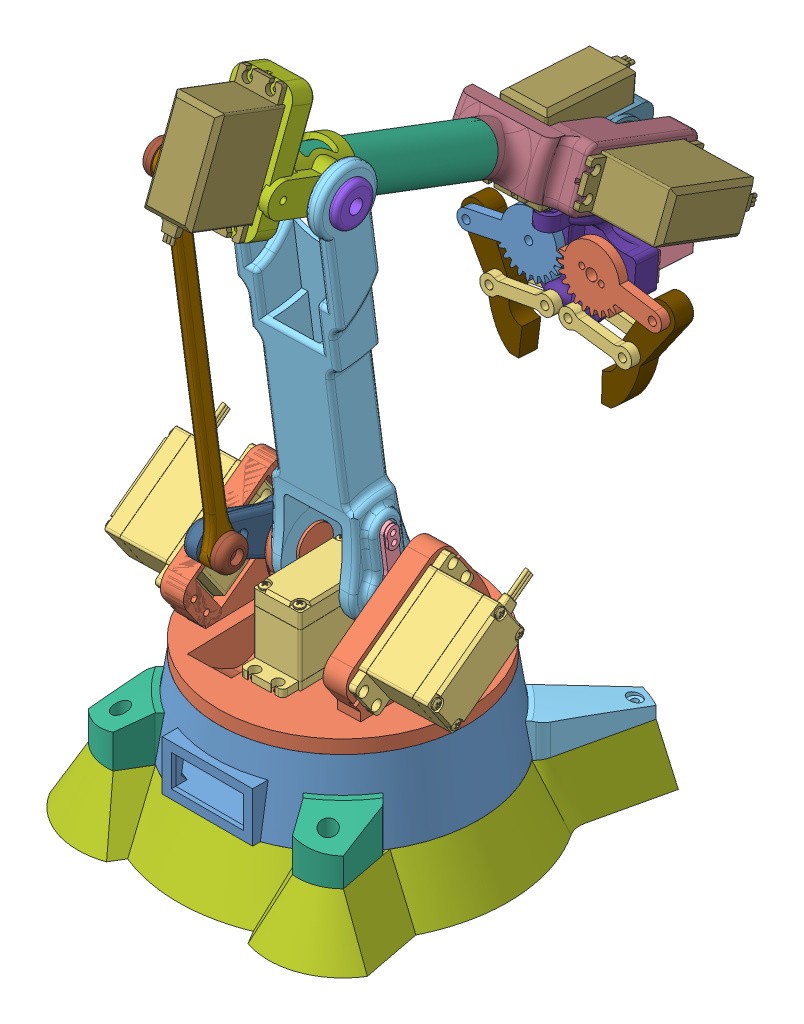
SolidWorks assembly Ensamblaje_BrazoAntropomorfico, configuration Predeterminado. Lengths in mm.
Overall size (151.9 310.82 225.14).
38 component instances, 26 part files, 98 mates.
Components (placement in the parent):
- Base_A-1: Base_A [Predeterminado] at (-3.433 0.4074 120) size (120 34 120)
- Shoulder-1: Shoulder [Predeterminado] at (-7.5517 101.6574 271.2283) x (-0.999641 0 0.026796) z (0 -1 0) size (110 110 66.97)
- DS3225MG-1: DS3225MG [Default] at (-3.433 -8.1926 120) x (0.026796 0 0.999641) z (0 -1 0) size (62.25 20.4 45.91)
- sk7_2-1: sk7_2 [По умолчанию] at (-3.433 -4.5926 120) x (0.707107 0 -0.707107) z (0 -1 0) size (34.33 14.5 6)
- UpperArm-1: UpperArm [Predeterminado] at (-2.865 194.9971 141.1893) x (-0.999641 0 0.026796) z (-0.02656 0.132481 -0.99083) size (45.4 189 30)
- LowerArm_B-1: LowerArm_B [Predeterminado] at (-3.0969 113.8716 19.1086) x (0.999641 0 -0.026796) z (-0.009844 0.930079 -0.367227) size (20 100 20)
- Elbow_A-1: Elbow_A [Predeterminado] at (-2.865 194.9971 141.1893) x (0.999641 0 -0.026796) z (0.009844 -0.930079 0.367227) size (39.5 63 55)
- Elbow_B-1: Elbow_B [Predeterminado] at (4.2269 149.451 93.4114) x (0.999641 0 -0.026796) z (0.016662 0.783182 0.621569) size (9.4 18 18)
- Elbow_B-2: Elbow_B [Predeterminado] at (-9.4831 203.9334 206.6401) x (-0.999641 0 0.026796) z (-0.026796 0 -0.999641) size (9.4 18 18)
- sk7_2-2: sk7_2 [По умолчанию] at (-37.1209 36.4074 120.903) x (0.024922 0.367359 0.929745) z (0.999641 0 -0.026796) size (34.33 14.5 6)
- sk7_2-3: sk7_2 [По умолчанию] at (21.2582 36.4074 119.3381) x (0.00355 0.991186 0.132433) z (-0.999641 0 0.026796) size (34.33 14.5 6)
- DS3225MG-2: DS3225MG [Default] at (17.4595 36.4074 119.44) x (0.02195 -0.573576 0.818858) z (-0.999641 0 0.026796) size (62.25 20.4 45.91)
- DS3225MG-3: DS3225MG [Default] at (-33.3222 36.4074 120.8012) x (0.02195 -0.573576 0.818858) z (0.999641 0 -0.026796) size (62.25 20.4 45.91)
- Elbow_C-1: Elbow_C [Predeterminado] at (-44.9671 11.6675 218.9112) x (-0.999641 0 0.026796) z (-0.02656 0.132481 -0.99083) size (5.67 174 14)
- Elbow_E-1: Elbow_E [Predeterminado] at (-7.0649 232.3614 275.5713) x (-0.999641 0 0.026796) z (-0.024922 -0.367359 -0.929745) size (16 20 57)
- Elbow_D-1: Elbow_D [Predeterminado] at (-46.6763 121.703 173.8077) x (-0.999641 0 0.026796) z (0.006088 -0.973848 0.227119) size (5 14 14)
- Elbow_D-2: Elbow_D [Predeterminado] at (4.4293 190.8188 108.4261) x (0.999641 0 -0.026796) z (0.026363 -0.179135 0.983471) size (5 14 14)
- Servo Motor MG996R_r1-1: Servo Motor MG996R_r1 [Default] at (-1.4531 226.8291 193.8608) x (-0.009844 0.930079 -0.367227) z (-0.999641 0 0.026796) size (55.8 47.4 21)
- LowerArm_A-1: LowerArm_A [Predeterminado] at (-22.8328 142.9423 9.885) x (0.999641 0 -0.026796) z (-0.009844 0.930079 -0.367227) size (52 84.05 26.47)
- Wrist_A-1: Wrist_A [Predeterminado] at (-61.7574 140.4489 24.7051) x (0.026699 0.08517 0.996009) z (0.999641 0 -0.026796) size (55 24 14.25)
- Wrist_B-1: Wrist_B [Predeterminado] at (-61.7574 140.4489 24.7051) x (0.026699 0.08517 0.996009) z (0.999641 0 -0.026796) size (55 24 18.05)
- Wrist_C-1: Wrist_C [Predeterminado] at (-62.2314 130.9865 18.2195) x (0.019428 -0.688723 0.724764) z (0.999641 0 -0.026796) size (18 18 10)
- Servo Motor MG996R_r1-2: Servo Motor MG996R_r1 [Default] at (55.5368 146.7077 17.321) x (0.024922 0.367359 0.929745) z (0.009844 -0.930079 0.367227) size (55.8 47.4 21)
- Servo Motor MG996R_r1-3: Servo Motor MG996R_r1 [Default] at (-6.1299 168.7244 17.5237) x (0.026699 0.08517 0.996009) z (0.999641 0 -0.026796) size (55.8 47.4 21)
- GripperBase-1: GripperBase [Predeterminado] at (-6.3231 100.4621 10.3139) x (0.999641 0 -0.026796) z (0.002282 -0.996366 0.085139) size (44.63 32 47.5)
- Gripper-1: Gripper [Predeterminado] at (-23.7562 61.3982 12.6156) x (0.99856 -0.048641 -0.022608) z (-0.046522 -0.995178 0.086346) size (30.3 8.5 47.24)
- GripperGearB-1: GripperGearB [Default] at (-29.6263 99.3082 18.0653) x (-0.984031 -0.173168 0.041185) z (-0.175984 0.981203 -0.079186) size (45.54 4 26.63)
- GripperGearA-1: GripperGearA [Default] at (-2.2327 104.0878 16.9223) x (-0.954015 0.299759 -0.00006) z (0.298568 0.950206 -0.089256) size (45.31 4 26.63)
- GripperLink-1: GripperLink [Default] at (-10.982 81.4716 23.1068) x (-0.988557 -0.145728 0.03896) z (0.148465 -0.985652 0.080305) size (32 4 8)
- Gripper-2: Gripper [Predeterminado] at (11.4351 62.1221 20.1445) x (-0.998338 -0.048641 0.03092) z (0.051081 -0.995178 0.08373) size (30.3 8.5 47.24)
- GripperLink-2: GripperLink [Default] at (22.7558 77.9742 22.5015) x (-0.989225 0.145728 0.014055) z (-0.14395 -0.985652 0.088143) size (32 4 8)
- GripperLink-3: GripperLink [Default] at (22.422 76.9095 10.0514) x (-0.989225 0.145728 0.014055) z (-0.14395 -0.985652 0.088143) size (32 4 8)
- GripperLink-4: GripperLink [Default] at (-11.3158 80.407 10.6567) x (-0.988557 -0.145728 0.03896) z (0.148465 -0.985652 0.080305) size (32 4 8)
- MG90s_servo-1: MG90s_servo [Default] at (1.489 99.7126 1.3334) x (0.999641 0 -0.026796) z (-0.026699 -0.08517 -0.996009) size (32.5 12 34)
- Base_C-1: Base_C [Predeterminado] at (12.125 2.808 0) size (121.27 15 51.87)
- Base_B-1: Base_B [Predeterminado] at (-18.9909 2.808 240) x (-1 0 0) z (0 0 -1) size (112.88 20 32.62)
- Base_D-1: Base_D [Predeterminado] at (5.8187 -22.0537 -33.2668) size (151.29 25.02 164)
- CableRetainer-1: CableRetainer [Predeterminado] at (12.125 4.808 0) size (22.02 11 22.02)
Mates (geometry in assembly coordinates):
- Concéntrica2: concentric aligned: cylinder of Base-1 through (-3.433 0.4074 120) axis (0 1 0) radius 49; cylinder of Hombro-1 through (-3.433 3.4074 120) axis (0 1 0) radius 55
- Coincidente1: coincident anti-aligned: plane of Base-1 through (-3.433 -10.5926 120) normal (0 1 0); plane of sk7_2-1 through (-3.433 -10.5926 120) normal (0 -1 0)
- Concéntrica3: concentric anti-aligned: cylinder of Base-1 through (-3.433 -6.5926 120) axis (0 -1 0) radius 7.7; cylinder of sk7_2-1 through (-3.433 -8.3926 120) axis (0 1 0) radius 2.75
- Paralelo1: parallel anti-aligned: plane of Base-1 through (7.0636 -6.5926 115.0896) normal (-0.707107 0 -0.707107); plane of sk7_2-1 through (-1.2409 -10.5926 122.192) normal (0.707107 0 0.707107)
- Coincidente4: coincident anti-aligned: plane of Base-1 through (-3.433 0.4074 65) normal (0 1 0); plane of Hombro-1 through (-7.5517 0.4074 271.2283) normal (0 -1 0)
- Coincidente5: coincident anti-aligned: plane of Hombro-1 through (-3.433 6.4074 120) normal (0 1 0); plane of DS3225MG-1 through (-3.433 6.4074 120) normal (0 -1 0)
- Concéntrica4: concentric anti-aligned: cylinder of Base-1 through (-3.433 -14.5926 120) axis (0 1 0) radius 1.45; cylinder of DS3225MG-1 through (-3.433 -8.1926 120) axis (0 -1 0) radius 1.25
- Concéntrica5: concentric aligned: cylinder of Hombro-1 through (2.4977 -7.5926 154.6535) axis (0 1 0) radius 1.45; cylinder of DS3225MG-1 through (2.4977 -8.1926 154.6535) axis (0 1 0) radius 2.25
- Concéntrica7: concentric aligned: cylinder of Hombro-1 through (-14.9288 36.4074 120.3082) axis (-0.999641 0 0.026796) radius 7.8; cylinder of Antebrazo-1 through (-9.9306 36.4074 120.1742) axis (-0.999641 0 0.026796) radius 8
- Coincidente7: coincident anti-aligned: plane of Hombro-1 through (-19.927 36.4074 120.4421) normal (0.999641 0 -0.026796); plane of Antebrazo-1 through (-19.927 36.4074 120.4421) normal (-0.999641 0 0.026796)
- Coincidente8: coincident anti-aligned: plane of Antebrazo-1 through (-2.865 194.9971 141.1893) normal (-0.999641 0 0.026796); plane of Codo_A-1 through (-2.865 194.9971 141.1893) normal (0.999641 0 -0.026796)
- Concéntrica8: concentric anti-aligned: cylinder of Antebrazo-1 through (-25.5568 194.9971 141.7976) axis (0.999641 0 -0.026796) radius 6.15; cylinder of Codo_A-1 through (-15.3605 194.9971 141.5242) axis (-0.999641 0 0.026796) radius 1.65
- Concéntrica9: concentric aligned: cylinder of Antebrazo-1 through (-25.5568 194.9971 141.7976) axis (0.999641 0 -0.026796) radius 6.15; cylinder of Codo_B-1 through (-21.6582 194.9971 141.6931) axis (0.999641 0 -0.026796) radius 6
- Paralelo2: parallel anti-aligned: plane of Codo_A-1 through (-21.4038 199.2929 139.9889) normal (-0.020986 0.621793 -0.782901); plane of Codo_B-1 through (-21.706 199.5077 139.9121) normal (0.020986 -0.621793 0.782901)
- Coincidente10: coincident anti-aligned: plane of Antebrazo-1 through (-25.5568 194.9971 141.7976) normal (-0.999641 0 0.026796); plane of Codo_B-1 through (-25.5568 194.9971 141.7976) normal (0.999641 0 -0.026796)
- Concéntrica10: concentric aligned: cylinder of Codo_A-1 through (9.6305 194.9971 140.8543) axis (0.999641 0 -0.026796) radius 1.65; cylinder of Codo_B-2 through (8.9308 194.9971 140.8731) axis (0.999641 0 -0.026796) radius 1.5
- Coincidente11: coincident anti-aligned: plane of Antebrazo-1 through (19.8269 194.9971 140.581) normal (0.999641 0 -0.026796); plane of Codo_B-2 through (19.8269 194.9971 140.581) normal (-0.999641 0 0.026796)
- Concéntrica11: concentric aligned: cylinder of Hombro-1 through (19.8106 48.9921 110.118) axis (0.999641 0 -0.026796) radius 1.35; cylinder of DS3225MG-2 through (17.2115 48.9921 110.1877) axis (0.999641 0 -0.026796) radius 2.25
- Concéntrica12: concentric aligned: cylinder of Hombro-1 through (20.7456 12.3511 144.9997) axis (0.999641 0 -0.026796) radius 1.35; cylinder of DS3225MG-2 through (18.1465 12.3511 145.0694) axis (0.999641 0 -0.026796) radius 2.25
- Concéntrica13: concentric anti-aligned: cylinder of sk7_2-3 through (17.4595 36.4074 119.44) axis (0.999641 0 -0.026796) radius 2.75; circle of DS3225MG-2
- Coincidente12: coincident anti-aligned: plane of sk7_2-3 through (17.4595 36.4074 119.44) normal (0.999641 0 -0.026796); plane of DS3225MG-2 through (17.4595 36.4074 119.44) normal (-0.999641 0 0.026796)
- Coincidente15: coincident anti-aligned: plane of Hombro-1 through (32.8041 22.0628 147.0217) normal (0.999641 0 -0.026796); plane of DS3225MG-2 through (32.0543 36.4074 119.0487) normal (-0.999641 0 0.026796)
- Concéntrica15: concentric aligned: cylinder of Antebrazo-1 through (-25.8397 60.1958 123.7813) axis (0.999641 0 -0.026796) radius 1.5; cylinder of sk7_2-3 through (15.3455 60.1958 122.6773) axis (0.999641 0 -0.026796) radius 1.25
- Concéntrica16: concentric anti-aligned: cylinder of Hombro-1 through (-57.0727 20.5427 152.8235) axis (0.999641 0 -0.026796) radius 1.35; cylinder of DS3225MG-3 through (-32.4815 20.5427 152.1643) axis (-0.999641 0 0.026796) radius 2.25
- Concéntrica17: concentric anti-aligned: cylinder of Hombro-1 through (-58.3151 40.8005 106.4744) axis (0.999641 0 -0.026796) radius 1.35; cylinder of DS3225MG-3 through (-33.7239 40.8005 105.8153) axis (-0.999641 0 0.026796) radius 2.25
- Concéntrica18: concentric aligned: cylinder of sk7_2-2 through (-33.3222 36.4074 120.8012) axis (-0.999641 0 0.026796) radius 2.75; cylinder of EjeCodo_B-1 through (-24.1255 36.4074 120.5547) axis (-0.999641 0 0.026796) radius 1.5
- Coincidente17: coincident anti-aligned: plane of sk7_2-2 through (-31.123 36.4074 120.7422) normal (0.999641 0 -0.026796); plane of EjeCodo_B-1 through (-30.1261 51.1017 157.9321) normal (-0.999641 0 0.026796)
- Concéntrica19: concentric anti-aligned: cylinder of sk7_2-2 through (-30.5249 45.224 143.0561) axis (-0.999641 0 0.026796) radius 1.25; cylinder of EjeCodo_B-1 through (-33.5238 45.224 143.1365) axis (0.999641 0 -0.026796) radius 1.5
- Concéntrica20: concentric anti-aligned: cylinder of sk7_2-2 through (-33.3222 36.4074 120.8012) axis (-0.999641 0 0.026796) radius 2.75; cylinder of DS3225MG-3 through (-33.3222 36.4074 120.8012) axis (0.999641 0 -0.026796) radius 1.25
- Coincidente18: coincident anti-aligned: plane of sk7_2-2 through (-33.3222 36.4074 120.8012) normal (-0.999641 0 0.026796); plane of DS3225MG-3 through (-33.3222 36.4074 120.8012) normal (0.999641 0 -0.026796)
- Coincidente19: coincident anti-aligned: plane of Hombro-1 through (-47.1484 22.1505 149.8663) normal (-0.999641 0 0.026796); plane of DS3225MG-3 through (-47.917 36.4074 121.1924) normal (0.999641 0 -0.026796)
- Concéntrica21: concentric anti-aligned: cylinder of EjeCodo_A-1 through (-24.928 51.1017 157.7927) axis (0.999641 0 -0.026796) radius 3.65; cylinder of EjeCodo_B-1 through (-18.1304 51.1017 157.6105) axis (-0.999641 0 0.026796) radius 3.5
- Concéntrica22: concentric aligned: cylinder of Codo_A-1 through (-22.8605 209.6914 178.9418) axis (0.999641 0 -0.026796) radius 3.5; cylinder of EjeCodo_A-1 through (-28.3586 209.6914 179.0892) axis (0.999641 0 -0.026796) radius 3.65
- Coincidente20: coincident anti-aligned: plane of Codo_A-1 through (-18.3594 194.9971 141.6046) normal (-0.999641 0 0.026796); plane of EjeCodo_A-1 through (-17.9305 51.1017 157.6051) normal (0.999641 0 -0.026796)
- Coincidente22: coincident anti-aligned: plane of EjeCodo_A-1 through (-17.9305 51.1017 157.6051) normal (0.999641 0 -0.026796); plane of EjeCodo_C-1 through (-17.9305 51.1017 157.6051) normal (-0.999641 0 0.026796)
- Concéntrica23: concentric anti-aligned: cylinder of EjeCodo_B-1 through (-14.1319 51.1017 157.5033) axis (-0.999641 0 0.026796) radius 1.45; cylinder of EjeCodo_C-1 through (-15.9312 51.1017 157.5516) axis (0.999641 0 -0.026796) radius 3
- Concéntrica24: concentric aligned: cylinder of Codo_A-1 through (-49.6868 209.6914 179.6609) axis (0.999641 0 -0.026796) radius 1.4; cylinder of EjeCodo_C-2 through (-27.8587 209.6914 179.0758) axis (0.999641 0 -0.026796) radius 1.4
- Coincidente23: coincident anti-aligned: plane of Codo_A-1 through (-22.8605 209.6914 178.9418) normal (-0.999641 0 0.026796); plane of EjeCodo_C-2 through (-22.8605 209.6914 178.9418) normal (0.999641 0 -0.026796)
- Concéntrica25: concentric anti-aligned: cylinder of Codo_A-1 through (2.307 234.3831 147.5376) axis (0.024922 0.367359 0.929745) radius 0.9; cylinder of Servo Motor MG996R_r1-1 through (2.7008 240.1874 162.2275) axis (-0.024922 -0.367359 -0.929745) radius 2.1
- Concéntrica26: concentric anti-aligned: cylinder of Codo_A-1 through (-7.2169 189.7393 165.4324) axis (0.024922 0.367359 0.929745) radius 0.9; cylinder of Servo Motor MG996R_r1-1 through (-6.8231 195.5436 180.1224) axis (-0.024922 -0.367359 -0.929745) radius 2.1
- Coincidente24: coincident anti-aligned: plane of Codo_A-1 through (-2.1298 205.8342 168.6168) normal (0.024922 0.367359 0.929745); plane of Servo Motor MG996R_r1-1 through (6.7473 240.7586 154.5795) normal (-0.024922 -0.367359 -0.929745)
- Coincidente25: coincident anti-aligned: plane of Brazo_B-1 through (-2.5335 199.8829 153.5549) normal (0.024922 0.367359 0.929745); plane of Servo Motor MG996R_r1-1 through (-2.5335 199.8829 153.5549) normal (-0.024922 -0.367359 -0.929745)
- Concéntrica27: concentric anti-aligned: cylinder of Brazo_B-1 through (-2.5335 199.8829 153.5549) axis (-0.024922 -0.367359 -0.929745) radius 10; cylinder of Codo_A-1 through (-3.2388 189.4867 127.2431) axis (0.024922 0.367359 0.929745) radius 10.2
- Concéntrica28: concentric aligned: cylinder of Brazo_B-1 through (-2.5335 199.8829 153.5549) axis (-0.024922 -0.367359 -0.929745) radius 8; cylinder of Brazo_A-1 through (-4.7267 167.5553 71.7373) axis (-0.024922 -0.367359 -0.929745) radius 7.8
- Paralelo3: parallel anti-aligned: plane of Brazo_B-1 through (-0.6105 207.0873 150.6568) normal (0.999641 0 -0.026796); plane of Brazo_A-1 through (-2.5649 171.0896 70.2829) normal (-0.999641 0 0.026796)
- Coincidente27: coincident anti-aligned: plane of Brazo_B-1 through (-5.0257 163.147 60.5804) normal (-0.024922 -0.367359 -0.929745); plane of Brazo_A-1 through (-5.0257 163.147 60.5804) normal (0.024922 0.367359 0.929745)
- Concéntrica29: concentric anti-aligned: cylinder of Brazo_A-1 through (11.705 142.5415 -5.6715) axis (0.999641 0 -0.026796) radius 0.6; cylinder of Servo Motor MG996R_r1-2 through (30.4982 142.5415 -6.1752) axis (-0.999641 0 0.026796) radius 2.1
- Concéntrica30: concentric anti-aligned: cylinder of Brazo_A-1 through (12.9997 150.8739 42.6286) axis (0.999641 0 -0.026796) radius 0.6; cylinder of Servo Motor MG996R_r1-2 through (31.7929 150.8739 42.1248) axis (-0.999641 0 0.026796) radius 2.1
- Coincidente28: coincident anti-aligned: plane of Brazo_A-1 through (25.0173 146.8965 43.1251) normal (0.999641 0 -0.026796); plane of Servo Motor MG996R_r1-2 through (23.5766 145.282 -10.6219) normal (-0.999641 0 0.026796)
- Coincidente29: coincident anti-aligned: plane of Muñeca_A-1 through (7.8984 142.9423 9.0612) normal (0.999641 0 -0.026796); plane of Servo Motor MG996R_r1-2 through (7.8984 142.9423 9.0612) normal (-0.999641 0 0.026796)
- Concéntrica31: concentric anti-aligned: cylinder of Muñeca_A-1 through (5.8991 142.9423 9.1148) axis (-0.999641 0 0.026796) radius 12; cylinder of Servo Motor MG996R_r1-2 through (7.8984 142.9423 9.0612) axis (0.999641 0 -0.026796) radius 10.5
- Coincidente30: coincident aligned: plane of Muñeca_A-1 through (-6.7984 137.6869 -7.4146) normal (0.002282 -0.996366 0.085139); plane of Muñeca_B-1 through (-7.3321 135.9841 -27.3273) normal (0.002282 -0.996366 0.085139)
- Coincidente31: coincident anti-aligned: plane of Muñeca_A-1 through (-6.7984 137.6869 -7.4146) normal (-0.999641 0 0.026796); plane of Muñeca_B-1 through (-7.3321 135.9841 -27.3273) normal (0.999641 0 -0.026796)
- Coincidente32: coincident aligned: plane of Muñeca_A-1 through (-62.3918 138.4253 1.0406) normal (0.026699 0.08517 0.996009); plane of Muñeca_B-1 through (-62.3918 138.4253 1.0406) normal (0.026699 0.08517 0.996009)
- Concéntrica32: concentric aligned: cylinder of Brazo_A-1 through (-27.8888 142.9423 10.0205) axis (0.999641 0 -0.026796) radius 6.2; cylinder of Muñeca_C-1 through (-24.8898 142.9423 9.9401) axis (0.999641 0 -0.026796) radius 6
- Coincidente33: coincident anti-aligned: plane of Brazo_A-1 through (-27.8888 142.9423 10.0205) normal (-0.999641 0 0.026796); plane of Muñeca_C-1 through (-27.8888 142.9423 10.0205) normal (0.999641 0 -0.026796)
- Concéntrica33: concentric aligned: cylinder of Muñeca_A-1 through (-1.7273 146.9523 -4.8288) axis (0.002282 -0.996366 0.085139) radius 0.6; cylinder of Servo Motor MG996R_r1-3 through (-1.7168 142.369 -4.4371) axis (0.002282 -0.996366 0.085139) radius 2.1
- Concéntrica34: concentric aligned: cylinder of Muñeca_B-1 through (-10.438 149.247 43.4009) axis (0.002282 -0.996366 0.085139) radius 0.6; cylinder of Servo Motor MG996R_r1-3 through (-10.4316 146.4571 43.6393) axis (0.002282 -0.996366 0.085139) radius 2.1
- Coincidente34: coincident anti-aligned: plane of Muñeca_B-1 through (-17.1534 143.7181 63.4444) normal (0.002282 -0.996366 0.085139); plane of Servo Motor MG996R_r1-3 through (-14.582 142.3542 47.4146) normal (-0.002282 0.996366 -0.085139)
- Concéntrica35: concentric aligned: cylinder of Servo Motor MG996R_r1-3 through (-6.2954 120.6237 11.3502) axis (-0.002282 0.996366 -0.085139) radius 10.5; cylinder of BaseGriper V3-1 through (-6.2954 120.6237 11.3502) axis (-0.002282 0.996366 -0.085139) radius 10.15
- Coincidente35: coincident anti-aligned: plane of Servo Motor MG996R_r1-3 through (-6.2954 120.6237 11.3502) normal (0.002282 -0.996366 0.085139); plane of BaseGriper V3-1 through (-6.2954 120.6237 11.3502) normal (-0.002282 0.996366 -0.085139)
- Concéntrica36: concentric aligned: cylinder of BaseGriper V3-1 through (-19.7615 100.8028 14.6611) axis (-0.026699 -0.08517 -0.996009) radius 1.4; cylinder of gear1_r1-1 through (-19.5746 101.399 21.6331) axis (-0.026699 -0.08517 -0.996009) radius 1.75
- Concéntrica37: concentric anti-aligned: cylinder of BaseGriper V3-1 through (7.3288 100.8028 13.9349) axis (-0.026699 -0.08517 -0.996009) radius 5; cylinder of gear2_r1-1 through (7.4089 101.0582 16.9219) axis (0.026699 0.08517 0.996009) radius 2.4
- Coincidente36: coincident anti-aligned: plane of BaseGriper V3-1 through (-19.9315 101.15 17.648) normal (0.026699 0.08517 0.996009); plane of gear1_r1-1 through (-27.3592 91.0159 18.7136) normal (-0.026699 -0.08517 -0.996009)
- Coincidente37: coincident aligned: plane of gear1_r1-1 through (-27.3592 91.0159 18.7136) normal (-0.026699 -0.08517 -0.996009); plane of gear2_r1-1 through (-21.9271 110.2759 16.9211) normal (-0.026699 -0.08517 -0.996009)
- Concéntrica39: concentric anti-aligned: cylinder of BaseGriper V3-1 through (-1.1725 80.8755 15.8668) axis (-0.026699 -0.08517 -0.996009) radius 1.4; cylinder of grip link 1_r1-3 through (-1.4261 80.0663 6.4047) axis (0.026699 0.08517 0.996009) radius 1.75
- Concéntrica40: concentric anti-aligned: cylinder of BaseGriper V3-1 through (-11.1689 80.8755 16.1347) axis (-0.026699 -0.08517 -0.996009) radius 1.4; cylinder of grip link 1_r1-1 through (-11.0888 81.131 19.1228) axis (0.026699 0.08517 0.996009) radius 1.75
- Concéntrica41: concentric anti-aligned: cylinder of BaseGriper V3-1 through (-1.1725 80.8755 15.8668) axis (-0.026699 -0.08517 -0.996009) radius 1.4; cylinder of grip link 1_r1-2 through (-1.0924 81.131 18.8548) axis (0.026699 0.08517 0.996009) radius 1.75
- Concéntrica42: concentric anti-aligned: cylinder of BaseGriper V3-1 through (-11.1689 80.8755 16.1347) axis (-0.026699 -0.08517 -0.996009) radius 1.4; cylinder of grip link 1_r1-4 through (-11.4225 80.0663 6.6727) axis (0.026699 0.08517 0.996009) radius 1.75
- Coincidente39: coincident anti-aligned: plane of BaseGriper V3-1 through (-11.0888 81.131 19.1228) normal (0.026699 0.08517 0.996009); plane of grip link 1_r1-1 through (-11.0888 81.131 19.1228) normal (-0.026699 -0.08517 -0.996009)
- Coincidente40: coincident anti-aligned: plane of BaseGriper V3-1 through (-11.3158 80.407 10.6567) normal (-0.026699 -0.08517 -0.996009); plane of grip link 1_r1-4 through (-11.3158 80.407 10.6567) normal (0.026699 0.08517 0.996009)
- Concéntrica45: concentric aligned: cylinder of Dedo-1 through (-46.2502 96.3828 18.7611) axis (-0.026699 -0.08517 -0.996009) radius 1.5; cylinder of gear1_r1-1 through (-46.1434 96.7234 22.7451) axis (-0.026699 -0.08517 -0.996009) radius 1.75
- Concéntrica47: concentric anti-aligned: cylinder of Dedo-1 through (-34.8142 77.6335 20.0578) axis (-0.026699 -0.08517 -0.996009) radius 1.5; cylinder of grip link 1_r1-1 through (-34.8142 77.6335 20.0578) axis (0.026699 0.08517 0.996009) radius 1.75
- Concéntrica48: concentric anti-aligned: cylinder of Dedo-1 through (-34.8142 77.6335 20.0578) axis (-0.026699 -0.08517 -0.996009) radius 1.5; cylinder of grip link 1_r1-4 through (-35.1479 76.5689 7.6077) axis (0.026699 0.08517 0.996009) radius 1.75
- Coincidente42: coincident anti-aligned: plane of Dedo-1 through (-46.4772 95.6588 10.295) normal (-0.026699 -0.08517 -0.996009); plane of grip link 1_r1-4 through (-11.3158 80.407 10.6567) normal (0.026699 0.08517 0.996009)
- Coincidente43: coincident anti-aligned: plane of gear2_r1-1 through (-21.9271 110.2759 16.9211) normal (-0.026699 -0.08517 -0.996009); plane of Dedo-2 through (33.9991 96.3828 16.61) normal (0.026699 0.08517 0.996009)
- Concéntrica49: concentric aligned: cylinder of gear2_r1-1 through (33.9991 96.3828 16.61) axis (0.026699 0.08517 0.996009) radius 1.75; cylinder of Dedo-2 through (33.7722 95.6588 8.1439) axis (0.026699 0.08517 0.996009) radius 1.5
- Coincidente44: coincident anti-aligned: plane of BaseGriper V3-1 through (-1.3193 80.407 10.3887) normal (-0.026699 -0.08517 -0.996009); plane of grip link 1_r1-3 through (22.422 76.9095 10.0514) normal (0.026699 0.08517 0.996009)
- Coincidente45: coincident anti-aligned: plane of BaseGriper V3-1 through (-1.0924 81.131 18.8548) normal (0.026699 0.08517 0.996009); plane of grip link 1_r1-2 through (22.649 77.6335 18.5175) normal (-0.026699 -0.08517 -0.996009)
- Concéntrica50: concentric aligned: cylinder of Dedo-2 through (22.422 76.9095 10.0514) axis (0.026699 0.08517 0.996009) radius 1.5; cylinder of grip link 1_r1-3 through (22.3153 76.5689 6.0674) axis (0.026699 0.08517 0.996009) radius 1.75
- Concéntrica51: concentric aligned: cylinder of Dedo-2 through (22.422 76.9095 10.0514) axis (0.026699 0.08517 0.996009) radius 1.5; cylinder of grip link 1_r1-2 through (22.649 77.6335 18.5175) axis (0.026699 0.08517 0.996009) radius 1.75
- Simétrico3: symmetric aligned: plane of BaseGriper V3-1 through (-6.3231 100.4621 10.3139) normal (0.999641 0 -0.026796); plane of Dedo-2 through (-23.3432 66.1028 20.7363) normal (0.99856 -0.048641 -0.022608); plane of Dedo-1 through (11.0039 65.3789 11.3435) normal (-0.998338 -0.048641 0.03092)
- Concéntrica52: concentric aligned: cylinder of BaseGriper V3-1 through (15.759 100.5899 11.2171) axis (-0.026699 -0.08517 -0.996009) radius 0.9; cylinder of MG90s_servo-1 through (15.5454 99.9085 3.249) axis (-0.026699 -0.08517 -0.996009) radius 1
- Concéntrica53: concentric aligned: cylinder of BaseGriper V3-1 through (-12.231 100.5899 11.9674) axis (-0.026699 -0.08517 -0.996009) radius 0.9; cylinder of MG90s_servo-1 through (-12.4446 99.9085 3.9993) axis (-0.026699 -0.08517 -0.996009) radius 1
- Coincidente46: coincident anti-aligned: plane of BaseGriper V3-1 through (-13.9583 106.1358 3.5074) normal (-0.026699 -0.08517 -0.996009); plane of MG90s_servo-1 through (1.5504 99.9085 3.6242) normal (0.026699 0.08517 0.996009)
- Coincidente51: coincident aligned: plane of Base-1 through (-3.433 -33.5926 120) normal (0 -1 0); plane of Patas Delanteras-1 through (21.4547 -33.5926 86.627) normal (0 -1 0)
- Concéntrica54: concentric anti-aligned: cylinder of Base-1 through (-40.5561 -29.2926 82.8769) axis (0 1 0) radius 1.45; cylinder of Patas Delanteras-1 through (-40.5561 -30.5926 82.8769) axis (0 -1 0) radius 3
- Concéntrica55: concentric aligned: cylinder of Base-1 through (33.6901 -29.2926 82.8769) axis (0 1 0) radius 1.45; cylinder of Patas Delanteras-1 through (33.6901 -35.4926 82.8769) axis (0 1 0) radius 1.45
- Coincidente52: coincident aligned: plane of Base-1 through (-3.433 -33.5926 120) normal (0 -1 0); plane of Patas Traseras-1 through (-28.3206 -33.5926 153.373) normal (0 -1 0)
- Concéntrica56: concentric anti-aligned: cylinder of Base-1 through (-40.5561 -29.2926 157.1231) axis (0 1 0) radius 1.45; cylinder of Patas Traseras-1 through (-40.5561 -30.5926 157.1231) axis (0 -1 0) radius 3
- Paralelo7: parallel aligned: plane of Antebrazo-1 through (-18.0755 210.1995 133.5371) normal (-0.999641 0 0.026796); plane of Brazo_A-1 through (-25.8895 142.9423 9.9669) normal (-0.999641 0 0.026796)
- Paralelo10: parallel aligned: plane of Muñeca_B-1 through (-62.5787 137.8291 -5.9315) normal (-0.026699 -0.08517 -0.996009); plane of MG90s_servo-1 through (0.9283 97.924 -19.5828) normal (-0.026699 -0.08517 -0.996009)
- Concéntrica57: concentric: cylinder of Patas Delanteras-1 through (-57.8031 -23.0926 45.1659) axis (0 -1 0) radius 3; cylinder of Pieza1-1 through (-57.8031 -30.838 45.1659) axis (0 -1 0) radius 1.5
- Concéntrica58: concentric: cylinder of Patas Delanteras-1 through (50.9372 -23.5926 45.1659) axis (0 -1 0) radius 1.45; cylinder of Pieza1-1 through (50.9372 -20.8647 45.1659) axis (0 -1 0) radius 1.5
- Coincidente54: coincident anti-aligned: plane of Patas Delanteras-1 through (21.4547 -33.5926 86.627) normal (0 -1 0); plane of Pieza1-1 through (-3.433 -33.5926 120) normal (0 1 0)
- Concéntrica59: concentric: cylinder of Base_A-1 through (-29.5959 -34.5926 93.837) axis (0 1 0) radius 1.45; cylinder of Retenedor de cable 3-1 through (-29.5959 -17.5926 93.837) axis (0 -1 0) radius 1.45
- Coincidente55: coincident: plane of Base_A-1 through (-29.5959 -28.5926 93.837) normal (0 1 0); plane of Retenedor de cable 3-1 through (-29.5959 -28.5926 93.837) normal (0 -1 0)
- Concéntrica60: concentric aligned: cylinder of Base_A-1 through (-17.5751 -30.5926 105.8579) axis (0 -1 0) radius 3; cylinder of Retenedor de cable 3-1 through (-17.5751 -17.5926 105.8579) axis (0 -1 0) radius 1.45
